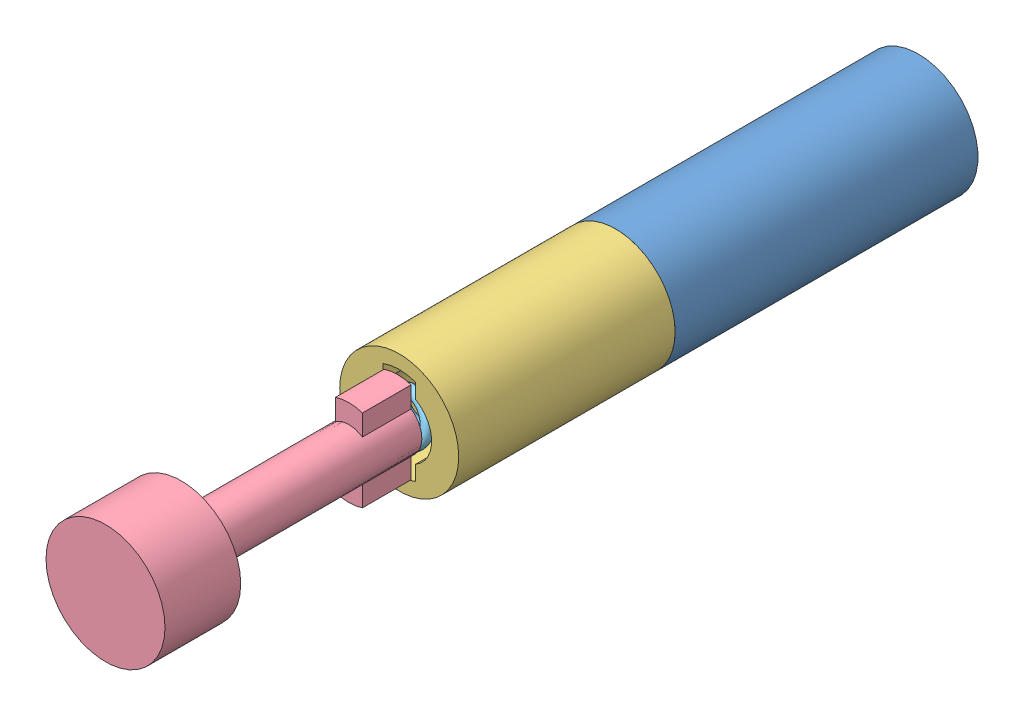
SolidWorks assembly Ensamblaje 2, configuration Predeterminado. Lengths in mm.
Overall size (22.09 22.09 152.38).
5 component instances, 5 part files, 5 mates.
Components (placement in the parent):
- Base motor y resorte-1: Base motor y resorte [Predeterminado] at (-0.2893 -0.5465 56) size (22 22 56)
- dc_motor-2: dc_motor [Default] at (-0.2893 -0.5465 63.6) x (0 0 -1) z (-1 0 0) size (62.2 10 12)
- enclaje-5: enclaje [Predeterminado] at (-0.2893 -0.5465 147) x (1 0 0) z (0 0 -1) size (22 22 40)
- Perno de anclaje y explusion-3: Perno de anclaje y explusion [Predeterminado] at (-0.2029 -0.6337 177.3848) x (1 0 0) z (0 0 -1) size (22 22 54)
- resorte - corregido-1: resorte - corregido [Predeterminado] at (-0.1931 -0.6243 83.5602) x (1 0 0) z (0 -1 0) size (9 72 9)
Mates (geometry in assembly coordinates):
- Coincidente2: coincident anti-aligned: plane of Base motor y resorte-1 through (-6.2893 4.4535 82) normal (0 -1 0); plane of dc_motor-2 through (-6.2893 4.4535 71.2) normal (0 1 0)
- Coincidente3: coincident: line of Base motor y resorte-1 through (-6.2893 4.4535 56) axis (0 -1 0); plane of dc_motor-2 through (-6.2893 4.4535 56) normal (0 0 -1)
- Coincidente4: coincident aligned: line of Base motor y resorte-1 through (-6.2893 4.4535 56) axis (0 -1 0); line of dc_motor-2 through (-6.2893 1.9535 56) axis (0 -1 0)
- Coincidente7: coincident anti-aligned: plane of Base motor y resorte-1 through (-0.2893 -0.5465 112) normal (0 0 1); plane of enclaje-5 through (-0.2893 -0.5465 112) normal (0 0 -1)
- Coincidente8: coincident anti-aligned: circle of Base motor y resorte-1; circle of enclaje-5
